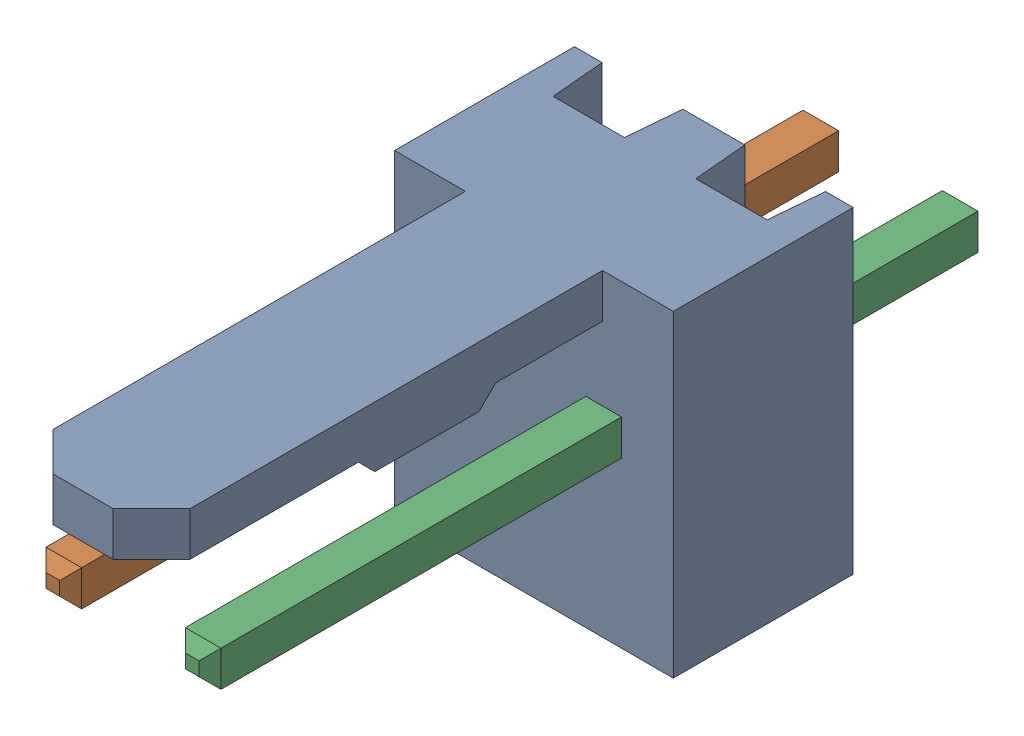
SolidWorks assembly Molex PCB 2 pin v2 (4), configuration Default. Lengths in mm.
Overall size (5.08 5.79 14.92).
3 component instances, 2 part files, 0 mates.
Components (placement in the parent):
- BASE9710016-1: BASE9710016 [Default] at (2.54 2.895 -8.22) size (5.08 5.79 11.5)
- PINO9710016-1: PINO9710016 [Default] at (1.27 3.325 -0.72) size (0.65 0.65 14.2)
- PINO9710016-2: PINO9710016 [Default] at (3.81 3.325 -0.72) size (0.65 0.65 14.2)
